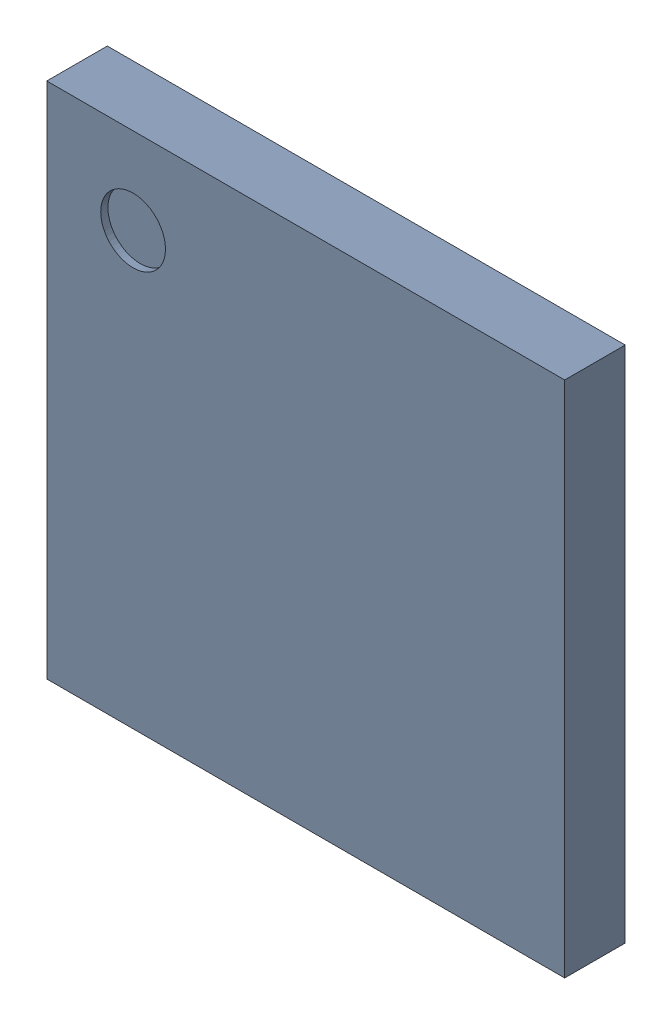
SolidWorks assembly U1.step, configuration Default. Lengths in mm.
Overall size (7.1 9.92 0.85).
188 component instances, 3 part files, 0 mates.
Components (placement in the parent):
- 6297727008.step-1: 6297727008.step [Default] at (115.1636 5.8674 0) x (1 0 0) z (0 0 1) size (7.1 9.92 0.85)
  - Body (5).step-1: Body (5).step [Default] at (-3.55 -3.55 0.02) size (7.1 7.1 0.83)
    - Open CASCADE STEP translator 6.8 9.2.1.step-1: Open CASCADE STEP translator 6.8 9.2.1.step [Default] at origin size (7.1 7.1 0.83)
  - Open CASCADE STEP translator 6.8 9.1.step-1: Open CASCADE STEP translator 6.8 9.1.step [Default] at (-3.55 -3.55 0.02) size (0.9 0.9 0.01)
  - pinShape.step-1: pinShape.step [Default] at (-3 -3 0.02) size (0.25 0.25 0.02)
  - pinShape.step-2: pinShape.step [Default] at (-2.75 -3 0.02) size (0.25 0.25 0.02)
  - pinShape.step-3: pinShape.step [Default] at (-2.5 -3 0.02) size (0.25 0.25 0.02)
  - pinShape.step-4: pinShape.step [Default] at (-2.25 -3 0.02) size (0.25 0.25 0.02)
  - pinShape.step-5: pinShape.step [Default] at (-2 -3 0.02) size (0.25 0.25 0.02)
  - pinShape.step-6: pinShape.step [Default] at (-1.75 -3 0.02) size (0.25 0.25 0.02)
  - pinShape.step-7: pinShape.step [Default] at (-1.5 -3 0.02) size (0.25 0.25 0.02)
  - pinShape.step-8: pinShape.step [Default] at (-1.25 -3 0.02) size (0.25 0.25 0.02)
  - pinShape.step-9: pinShape.step [Default] at (-1 -3 0.02) size (0.25 0.25 0.02)
  - pinShape.step-10: pinShape.step [Default] at (-0.75 -3 0.02) size (0.25 0.25 0.02)
  - pinShape.step-11: pinShape.step [Default] at (-0.5 -3 0.02) size (0.25 0.25 0.02)
  - pinShape.step-12: pinShape.step [Default] at (-0.25 -3 0.02) size (0.25 0.25 0.02)
  - pinShape.step-13: pinShape.step [Default] at (0 -3 0.02) size (0.25 0.25 0.02)
  - pinShape.step-14: pinShape.step [Default] at (0.25 -3 0.02) size (0.25 0.25 0.02)
  - pinShape.step-15: pinShape.step [Default] at (0.5 -3 0.02) size (0.25 0.25 0.02)
  - pinShape.step-16: pinShape.step [Default] at (0.75 -3 0.02) size (0.25 0.25 0.02)
  - pinShape.step-17: pinShape.step [Default] at (1 -3 0.02) size (0.25 0.25 0.02)
  - pinShape.step-18: pinShape.step [Default] at (1.25 -3 0.02) size (0.25 0.25 0.02)
  - pinShape.step-19: pinShape.step [Default] at (1.5 -3 0.02) size (0.25 0.25 0.02)
  - pinShape.step-20: pinShape.step [Default] at (1.75 -3 0.02) size (0.25 0.25 0.02)
  - pinShape.step-21: pinShape.step [Default] at (2 -3 0.02) size (0.25 0.25 0.02)
  - pinShape.step-22: pinShape.step [Default] at (2.25 -3 0.02) size (0.25 0.25 0.02)
  - pinShape.step-23: pinShape.step [Default] at (2.5 -3 0.02) size (0.25 0.25 0.02)
  - pinShape.step-24: pinShape.step [Default] at (2.75 -3 0.02) size (0.25 0.25 0.02)
  - pinShape.step-25: pinShape.step [Default] at (3 -3 0.02) size (0.25 0.25 0.02)
  - pinShape.step-26: pinShape.step [Default] at (-3 -2.75 0.02) size (0.25 0.25 0.02)
  - pinShape.step-27: pinShape.step [Default] at (-2.75 -2.75 0.02) size (0.25 0.25 0.02)
  - pinShape.step-28: pinShape.step [Default] at (-2.5 -2.75 0.02) size (0.25 0.25 0.02)
  - pinShape.step-29: pinShape.step [Default] at (-2.25 -2.75 0.02) size (0.25 0.25 0.02)
  - pinShape.step-30: pinShape.step [Default] at (-2 -2.75 0.02) size (0.25 0.25 0.02)
  - pinShape.step-31: pinShape.step [Default] at (-1.75 -2.75 0.02) size (0.25 0.25 0.02)
  - pinShape.step-32: pinShape.step [Default] at (-1.5 -2.75 0.02) size (0.25 0.25 0.02)
  - pinShape.step-33: pinShape.step [Default] at (-1.25 -2.75 0.02) size (0.25 0.25 0.02)
  - pinShape.step-34: pinShape.step [Default] at (-1 -2.75 0.02) size (0.25 0.25 0.02)
  - pinShape.step-35: pinShape.step [Default] at (-0.75 -2.75 0.02) size (0.25 0.25 0.02)
  - pinShape.step-36: pinShape.step [Default] at (-0.5 -2.75 0.02) size (0.25 0.25 0.02)
  - pinShape.step-37: pinShape.step [Default] at (-0.25 -2.75 0.02) size (0.25 0.25 0.02)
  - pinShape.step-38: pinShape.step [Default] at (0 -2.75 0.02) size (0.25 0.25 0.02)
  - pinShape.step-39: pinShape.step [Default] at (0.25 -2.75 0.02) size (0.25 0.25 0.02)
  - pinShape.step-40: pinShape.step [Default] at (0.5 -2.75 0.02) size (0.25 0.25 0.02)
  - pinShape.step-41: pinShape.step [Default] at (0.75 -2.75 0.02) size (0.25 0.25 0.02)
  - pinShape.step-42: pinShape.step [Default] at (1 -2.75 0.02) size (0.25 0.25 0.02)
  - pinShape.step-43: pinShape.step [Default] at (1.25 -2.75 0.02) size (0.25 0.25 0.02)
  - pinShape.step-44: pinShape.step [Default] at (1.5 -2.75 0.02) size (0.25 0.25 0.02)
  - pinShape.step-45: pinShape.step [Default] at (1.75 -2.75 0.02) size (0.25 0.25 0.02)
  - pinShape.step-46: pinShape.step [Default] at (2 -2.75 0.02) size (0.25 0.25 0.02)
  - pinShape.step-47: pinShape.step [Default] at (2.25 -2.75 0.02) size (0.25 0.25 0.02)
  - pinShape.step-48: pinShape.step [Default] at (2.5 -2.75 0.02) size (0.25 0.25 0.02)
  - pinShape.step-49: pinShape.step [Default] at (2.75 -2.75 0.02) size (0.25 0.25 0.02)
  - pinShape.step-50: pinShape.step [Default] at (3 -2.75 0.02) size (0.25 0.25 0.02)
  - pinShape.step-51: pinShape.step [Default] at (-3 -2.5 0.02) size (0.25 0.25 0.02)
  - pinShape.step-52: pinShape.step [Default] at (-2.75 -2.5 0.02) size (0.25 0.25 0.02)
  - pinShape.step-53: pinShape.step [Default] at (2.75 -2.5 0.02) size (0.25 0.25 0.02)
  - pinShape.step-54: pinShape.step [Default] at (3 -2.5 0.02) size (0.25 0.25 0.02)
  - pinShape.step-55: pinShape.step [Default] at (-3 -2.25 0.02) size (0.25 0.25 0.02)
  - pinShape.step-56: pinShape.step [Default] at (-2.75 -2.25 0.02) size (0.25 0.25 0.02)
  - pinShape.step-57: pinShape.step [Default] at (2.75 -2.25 0.02) size (0.25 0.25 0.02)
  - pinShape.step-58: pinShape.step [Default] at (3 -2.25 0.02) size (0.25 0.25 0.02)
  - pinShape.step-59: pinShape.step [Default] at (-3 -2 0.02) size (0.25 0.25 0.02)
  - pinShape.step-60: pinShape.step [Default] at (-2.75 -2 0.02) size (0.25 0.25 0.02)
  - pinShape.step-61: pinShape.step [Default] at (2.75 -2 0.02) size (0.25 0.25 0.02)
  - pinShape.step-62: pinShape.step [Default] at (3 -2 0.02) size (0.25 0.25 0.02)
  - pinShape.step-63: pinShape.step [Default] at (-3 -1.75 0.02) size (0.25 0.25 0.02)
  - pinShape.step-64: pinShape.step [Default] at (-2.75 -1.75 0.02) size (0.25 0.25 0.02)
  - pinShape.step-65: pinShape.step [Default] at (2.75 -1.75 0.02) size (0.25 0.25 0.02)
  - pinShape.step-66: pinShape.step [Default] at (3 -1.75 0.02) size (0.25 0.25 0.02)
  - pinShape.step-67: pinShape.step [Default] at (-3 -1.5 0.02) size (0.25 0.25 0.02)
  - pinShape.step-68: pinShape.step [Default] at (-2.75 -1.5 0.02) size (0.25 0.25 0.02)
  - pinShape.step-69: pinShape.step [Default] at (2.75 -1.5 0.02) size (0.25 0.25 0.02)
  - pinShape.step-70: pinShape.step [Default] at (3 -1.5 0.02) size (0.25 0.25 0.02)
  - pinShape.step-71: pinShape.step [Default] at (-3 -1.25 0.02) size (0.25 0.25 0.02)
  - pinShape.step-72: pinShape.step [Default] at (-2.75 -1.25 0.02) size (0.25 0.25 0.02)
  - pinShape.step-73: pinShape.step [Default] at (2.75 -1.25 0.02) size (0.25 0.25 0.02)
  - pinShape.step-74: pinShape.step [Default] at (3 -1.25 0.02) size (0.25 0.25 0.02)
  - pinShape.step-75: pinShape.step [Default] at (-3 -1 0.02) size (0.25 0.25 0.02)
  - pinShape.step-76: pinShape.step [Default] at (-2.75 -1 0.02) size (0.25 0.25 0.02)
  - pinShape.step-77: pinShape.step [Default] at (2.75 -1 0.02) size (0.25 0.25 0.02)
  - pinShape.step-78: pinShape.step [Default] at (3 -1 0.02) size (0.25 0.25 0.02)
  - pinShape.step-79: pinShape.step [Default] at (-3 -0.75 0.02) size (0.25 0.25 0.02)
  - pinShape.step-80: pinShape.step [Default] at (-2.75 -0.75 0.02) size (0.25 0.25 0.02)
  - pinShape.step-81: pinShape.step [Default] at (2.75 -0.75 0.02) size (0.25 0.25 0.02)
  - pinShape.step-82: pinShape.step [Default] at (3 -0.75 0.02) size (0.25 0.25 0.02)
  - pinShape.step-83: pinShape.step [Default] at (-3 -0.5 0.02) size (0.25 0.25 0.02)
  - pinShape.step-84: pinShape.step [Default] at (-2.75 -0.5 0.02) size (0.25 0.25 0.02)
  - pinShape.step-85: pinShape.step [Default] at (2.75 -0.5 0.02) size (0.25 0.25 0.02)
  - pinShape.step-86: pinShape.step [Default] at (3 -0.5 0.02) size (0.25 0.25 0.02)
  - pinShape.step-87: pinShape.step [Default] at (-3 -0.25 0.02) size (0.25 0.25 0.02)
  - pinShape.step-88: pinShape.step [Default] at (-2.75 -0.25 0.02) size (0.25 0.25 0.02)
  - pinShape.step-89: pinShape.step [Default] at (2.75 -0.25 0.02) size (0.25 0.25 0.02)
  - pinShape.step-90: pinShape.step [Default] at (3 -0.25 0.02) size (0.25 0.25 0.02)
  - pinShape.step-91: pinShape.step [Default] at (-3 0 0.02) size (0.25 0.25 0.02)
  - pinShape.step-92: pinShape.step [Default] at (-2.75 0 0.02) size (0.25 0.25 0.02)
  - pinShape.step-93: pinShape.step [Default] at (2.75 0 0.02) size (0.25 0.25 0.02)
  - pinShape.step-94: pinShape.step [Default] at (3 0 0.02) size (0.25 0.25 0.02)
  - pinShape.step-95: pinShape.step [Default] at (-3 0.25 0.02) size (0.25 0.25 0.02)
  - pinShape.step-96: pinShape.step [Default] at (-2.75 0.25 0.02) size (0.25 0.25 0.02)
  - pinShape.step-97: pinShape.step [Default] at (2.75 0.25 0.02) size (0.25 0.25 0.02)
  - pinShape.step-98: pinShape.step [Default] at (3 0.25 0.02) size (0.25 0.25 0.02)
  - pinShape.step-99: pinShape.step [Default] at (-3 0.5 0.02) size (0.25 0.25 0.02)
  - pinShape.step-100: pinShape.step [Default] at (-2.75 0.5 0.02) size (0.25 0.25 0.02)
  - pinShape.step-101: pinShape.step [Default] at (2.75 0.5 0.02) size (0.25 0.25 0.02)
  - pinShape.step-102: pinShape.step [Default] at (3 0.5 0.02) size (0.25 0.25 0.02)
  - pinShape.step-103: pinShape.step [Default] at (-3 0.75 0.02) size (0.25 0.25 0.02)
  - pinShape.step-104: pinShape.step [Default] at (-2.75 0.75 0.02) size (0.25 0.25 0.02)
  - pinShape.step-105: pinShape.step [Default] at (2.75 0.75 0.02) size (0.25 0.25 0.02)
  - pinShape.step-106: pinShape.step [Default] at (3 0.75 0.02) size (0.25 0.25 0.02)
  - pinShape.step-107: pinShape.step [Default] at (-3 1 0.02) size (0.25 0.25 0.02)
  - pinShape.step-108: pinShape.step [Default] at (-2.75 1 0.02) size (0.25 0.25 0.02)
  - pinShape.step-109: pinShape.step [Default] at (2.75 1 0.02) size (0.25 0.25 0.02)
  - pinShape.step-110: pinShape.step [Default] at (3 1 0.02) size (0.25 0.25 0.02)
  - pinShape.step-111: pinShape.step [Default] at (-3 1.25 0.02) size (0.25 0.25 0.02)
  - pinShape.step-112: pinShape.step [Default] at (-2.75 1.25 0.02) size (0.25 0.25 0.02)
  - pinShape.step-113: pinShape.step [Default] at (2.75 1.25 0.02) size (0.25 0.25 0.02)
  - pinShape.step-114: pinShape.step [Default] at (3 1.25 0.02) size (0.25 0.25 0.02)
  - pinShape.step-115: pinShape.step [Default] at (-3 1.5 0.02) size (0.25 0.25 0.02)
  - pinShape.step-116: pinShape.step [Default] at (-2.75 1.5 0.02) size (0.25 0.25 0.02)
  - pinShape.step-117: pinShape.step [Default] at (2.75 1.5 0.02) size (0.25 0.25 0.02)
  - pinShape.step-118: pinShape.step [Default] at (3 1.5 0.02) size (0.25 0.25 0.02)
  - pinShape.step-119: pinShape.step [Default] at (-3 1.75 0.02) size (0.25 0.25 0.02)
  - pinShape.step-120: pinShape.step [Default] at (-2.75 1.75 0.02) size (0.25 0.25 0.02)
  - pinShape.step-121: pinShape.step [Default] at (2.75 1.75 0.02) size (0.25 0.25 0.02)
  - pinShape.step-122: pinShape.step [Default] at (3 1.75 0.02) size (0.25 0.25 0.02)
  - pinShape.step-123: pinShape.step [Default] at (-3 2 0.02) size (0.25 0.25 0.02)
  - pinShape.step-124: pinShape.step [Default] at (-2.75 2 0.02) size (0.25 0.25 0.02)
  - pinShape.step-125: pinShape.step [Default] at (2.75 2 0.02) size (0.25 0.25 0.02)
  - pinShape.step-126: pinShape.step [Default] at (3 2 0.02) size (0.25 0.25 0.02)
  - pinShape.step-127: pinShape.step [Default] at (-3 2.25 0.02) size (0.25 0.25 0.02)
  - pinShape.step-128: pinShape.step [Default] at (-2.75 2.25 0.02) size (0.25 0.25 0.02)
  - pinShape.step-129: pinShape.step [Default] at (2.75 2.25 0.02) size (0.25 0.25 0.02)
  - pinShape.step-130: pinShape.step [Default] at (3 2.25 0.02) size (0.25 0.25 0.02)
  - pinShape.step-131: pinShape.step [Default] at (-3 2.5 0.02) size (0.25 0.25 0.02)
  - pinShape.step-132: pinShape.step [Default] at (-2.75 2.5 0.02) size (0.25 0.25 0.02)
  - pinShape.step-133: pinShape.step [Default] at (2.75 2.5 0.02) size (0.25 0.25 0.02)
  - pinShape.step-134: pinShape.step [Default] at (3 2.5 0.02) size (0.25 0.25 0.02)
  - pinShape.step-135: pinShape.step [Default] at (-3 2.75 0.02) size (0.25 0.25 0.02)
  - pinShape.step-136: pinShape.step [Default] at (-2.75 2.75 0.02) size (0.25 0.25 0.02)
  - pinShape.step-137: pinShape.step [Default] at (-2.5 2.75 0.02) size (0.25 0.25 0.02)
  - pinShape.step-138: pinShape.step [Default] at (-2.25 2.75 0.02) size (0.25 0.25 0.02)
  - pinShape.step-139: pinShape.step [Default] at (-2 2.75 0.02) size (0.25 0.25 0.02)
  - pinShape.step-140: pinShape.step [Default] at (-1.75 2.75 0.02) size (0.25 0.25 0.02)
  - pinShape.step-141: pinShape.step [Default] at (-1.5 2.75 0.02) size (0.25 0.25 0.02)
  - pinShape.step-142: pinShape.step [Default] at (-1.25 2.75 0.02) size (0.25 0.25 0.02)
  - pinShape.step-143: pinShape.step [Default] at (-1 2.75 0.02) size (0.25 0.25 0.02)
  - pinShape.step-144: pinShape.step [Default] at (-0.75 2.75 0.02) size (0.25 0.25 0.02)
  - pinShape.step-145: pinShape.step [Default] at (-0.5 2.75 0.02) size (0.25 0.25 0.02)
  - pinShape.step-146: pinShape.step [Default] at (-0.25 2.75 0.02) size (0.25 0.25 0.02)
  - pinShape.step-147: pinShape.step [Default] at (0 2.75 0.02) size (0.25 0.25 0.02)
  - pinShape.step-148: pinShape.step [Default] at (0.25 2.75 0.02) size (0.25 0.25 0.02)
  - pinShape.step-149: pinShape.step [Default] at (0.5 2.75 0.02) size (0.25 0.25 0.02)
  - pinShape.step-150: pinShape.step [Default] at (0.75 2.75 0.02) size (0.25 0.25 0.02)
  - pinShape.step-151: pinShape.step [Default] at (1 2.75 0.02) size (0.25 0.25 0.02)
  - pinShape.step-152: pinShape.step [Default] at (1.25 2.75 0.02) size (0.25 0.25 0.02)
  - pinShape.step-153: pinShape.step [Default] at (1.5 2.75 0.02) size (0.25 0.25 0.02)
  - pinShape.step-154: pinShape.step [Default] at (1.75 2.75 0.02) size (0.25 0.25 0.02)
  - pinShape.step-155: pinShape.step [Default] at (2 2.75 0.02) size (0.25 0.25 0.02)
  - pinShape.step-156: pinShape.step [Default] at (2.25 2.75 0.02) size (0.25 0.25 0.02)
  - pinShape.step-157: pinShape.step [Default] at (2.5 2.75 0.02) size (0.25 0.25 0.02)
  - pinShape.step-158: pinShape.step [Default] at (2.75 2.75 0.02) size (0.25 0.25 0.02)
  - pinShape.step-159: pinShape.step [Default] at (3 2.75 0.02) size (0.25 0.25 0.02)
  - pinShape.step-160: pinShape.step [Default] at (-3 3 0.02) size (0.25 0.25 0.02)
  - pinShape.step-161: pinShape.step [Default] at (-2.75 3 0.02) size (0.25 0.25 0.02)
  - pinShape.step-162: pinShape.step [Default] at (-2.5 3 0.02) size (0.25 0.25 0.02)
  - pinShape.step-163: pinShape.step [Default] at (-2.25 3 0.02) size (0.25 0.25 0.02)
  - pinShape.step-164: pinShape.step [Default] at (-2 3 0.02) size (0.25 0.25 0.02)
  - pinShape.step-165: pinShape.step [Default] at (-1.75 3 0.02) size (0.25 0.25 0.02)
  - pinShape.step-166: pinShape.step [Default] at (-1.5 3 0.02) size (0.25 0.25 0.02)
  - pinShape.step-167: pinShape.step [Default] at (-1.25 3 0.02) size (0.25 0.25 0.02)
  - pinShape.step-168: pinShape.step [Default] at (-1 3 0.02) size (0.25 0.25 0.02)
  - pinShape.step-169: pinShape.step [Default] at (-0.75 3 0.02) size (0.25 0.25 0.02)
  - pinShape.step-170: pinShape.step [Default] at (-0.5 3 0.02) size (0.25 0.25 0.02)
  - pinShape.step-171: pinShape.step [Default] at (-0.25 3 0.02) size (0.25 0.25 0.02)
  - pinShape.step-172: pinShape.step [Default] at (0 3 0.02) size (0.25 0.25 0.02)
  - pinShape.step-173: pinShape.step [Default] at (0.25 3 0.02) size (0.25 0.25 0.02)
  - pinShape.step-174: pinShape.step [Default] at (0.5 3 0.02) size (0.25 0.25 0.02)
  - pinShape.step-175: pinShape.step [Default] at (0.75 3 0.02) size (0.25 0.25 0.02)
  - pinShape.step-176: pinShape.step [Default] at (1 3 0.02) size (0.25 0.25 0.02)
  - pinShape.step-177: pinShape.step [Default] at (1.25 3 0.02) size (0.25 0.25 0.02)
  - pinShape.step-178: pinShape.step [Default] at (1.5 3 0.02) size (0.25 0.25 0.02)
  - pinShape.step-179: pinShape.step [Default] at (1.75 3 0.02) size (0.25 0.25 0.02)
  - pinShape.step-180: pinShape.step [Default] at (2 3 0.02) size (0.25 0.25 0.02)
  - pinShape.step-181: pinShape.step [Default] at (2.25 3 0.02) size (0.25 0.25 0.02)
  - pinShape.step-182: pinShape.step [Default] at (2.5 3 0.02) size (0.25 0.25 0.02)
  - pinShape.step-183: pinShape.step [Default] at (2.75 3 0.02) size (0.25 0.25 0.02)
  - pinShape.step-184: pinShape.step [Default] at (3 3 0.02) size (0.25 0.25 0.02)
